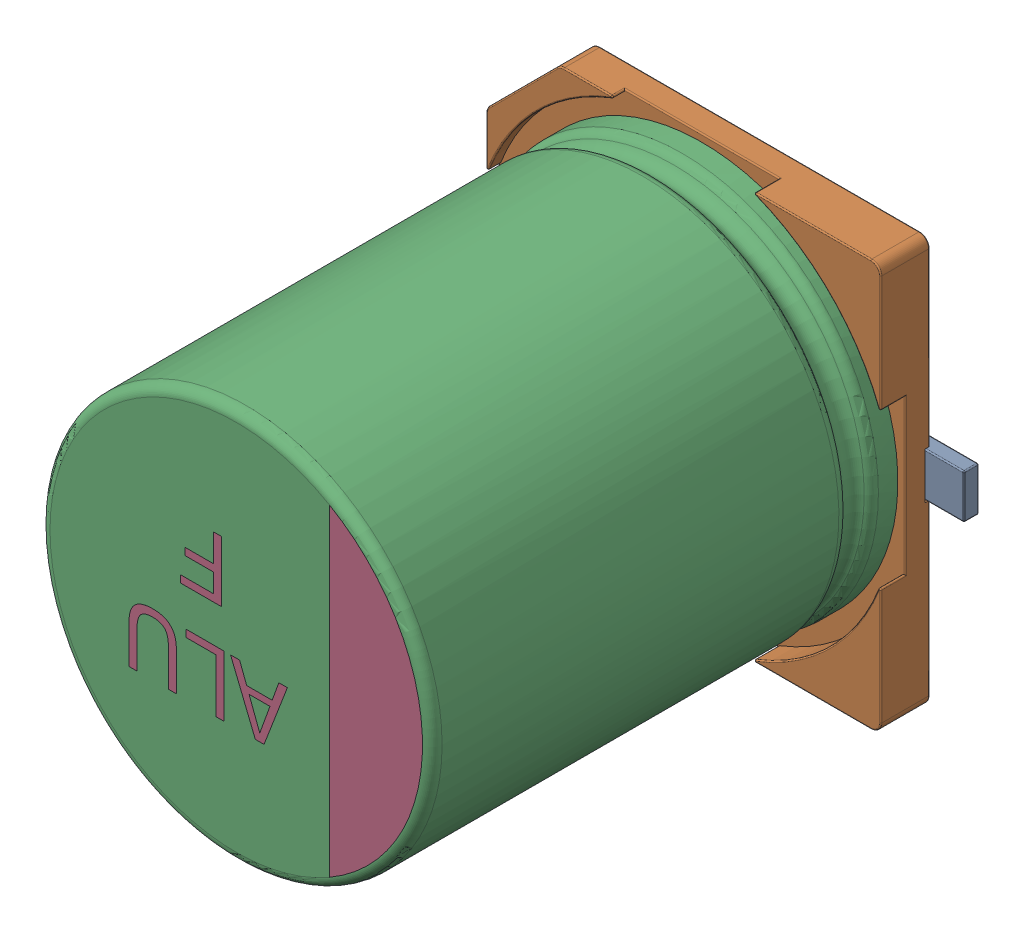
SolidWorks assembly C33主板_V1.0, configuration 默认. Lengths in mm.
Overall size (9.9 8.3 10.2).
5 component instances, 4 part files, 0 mates.
Components (placement in the parent):
- ALU-F_8.0x8.3x10.2-1: ALU-F_8.0x8.3x10.2 [默认] at (13.7778 37.769 0) x (-1 0 0) z (0 0 1) size (9.9 8.3 10.2)
  - User_Library-ALU-F_Pins_1-1: User_Library-ALU-F_Pins_1 [默认] at origin size (9.9 0.9 0.4)
  - User_Library-ALU-F_Fuss_1-1: User_Library-ALU-F_Fuss_1 [默认] at origin size (8.3 8.3 1)
  - User_Library-ALU-F_K_X_F6rper_1-1: User_Library-ALU-F_K_X_F6rper_1 [默认] at origin size (8 8 9.5)
  - User_Library-ALU-F_Beschriftung_1-1: User_Library-ALU-F_Beschriftung_1 [默认] at origin size (5.99 6.58 0.06)
